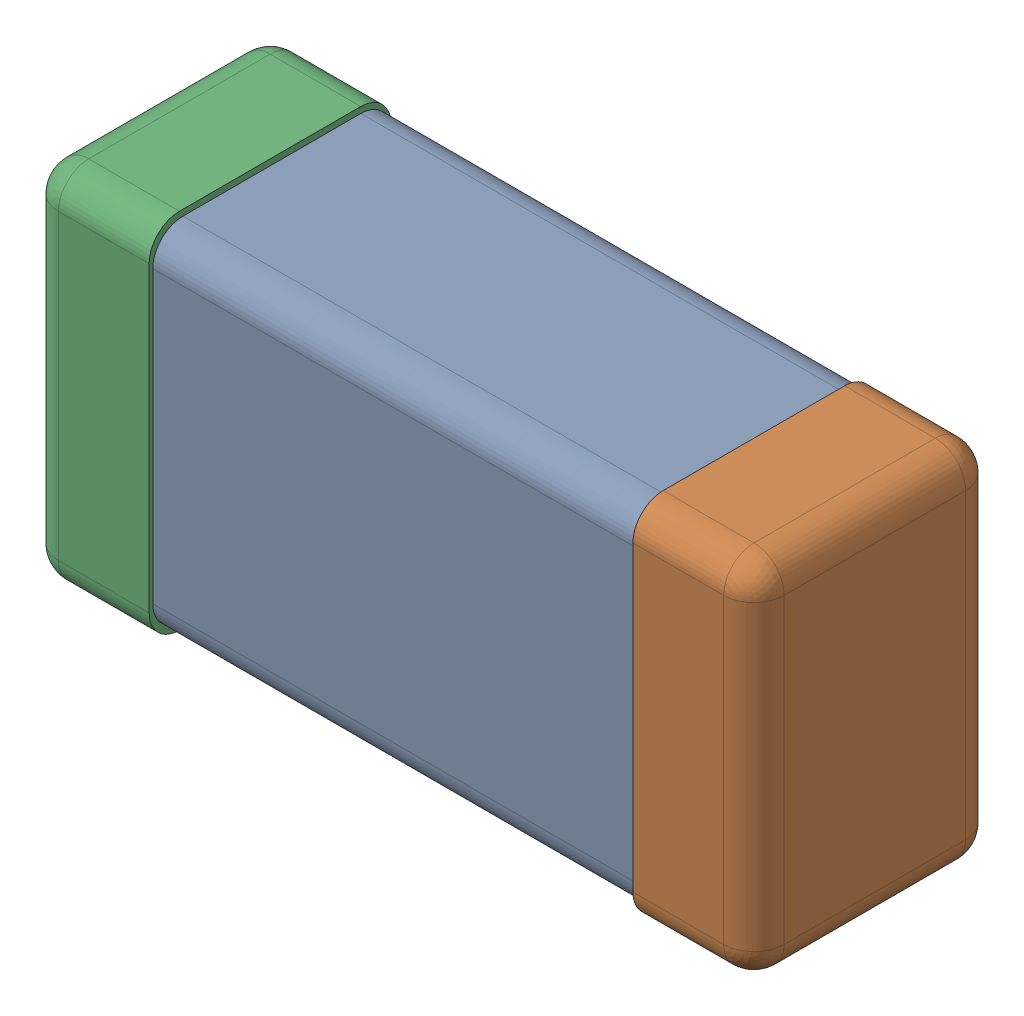
SolidWorks assembly C0201_020_23, configuration Standard. Lengths in mm.
Overall size (0.6 0.3 0.2).
3 component instances, 3 part files, 0 mates.
Components (placement in the parent):
- Part 3_2-1: Part 3_2 [Standard] at (0 0 -7.3015) size (0.5 0.29 0.2)
- Part 2_2-1: Part 2_2 [Standard] at (0 0 -7.3) size (0.1 0.3 0.2)
- Part 1_2-1: Part 1_2 [Standard] at (0 0 -7.3) size (0.1 0.3 0.2)
